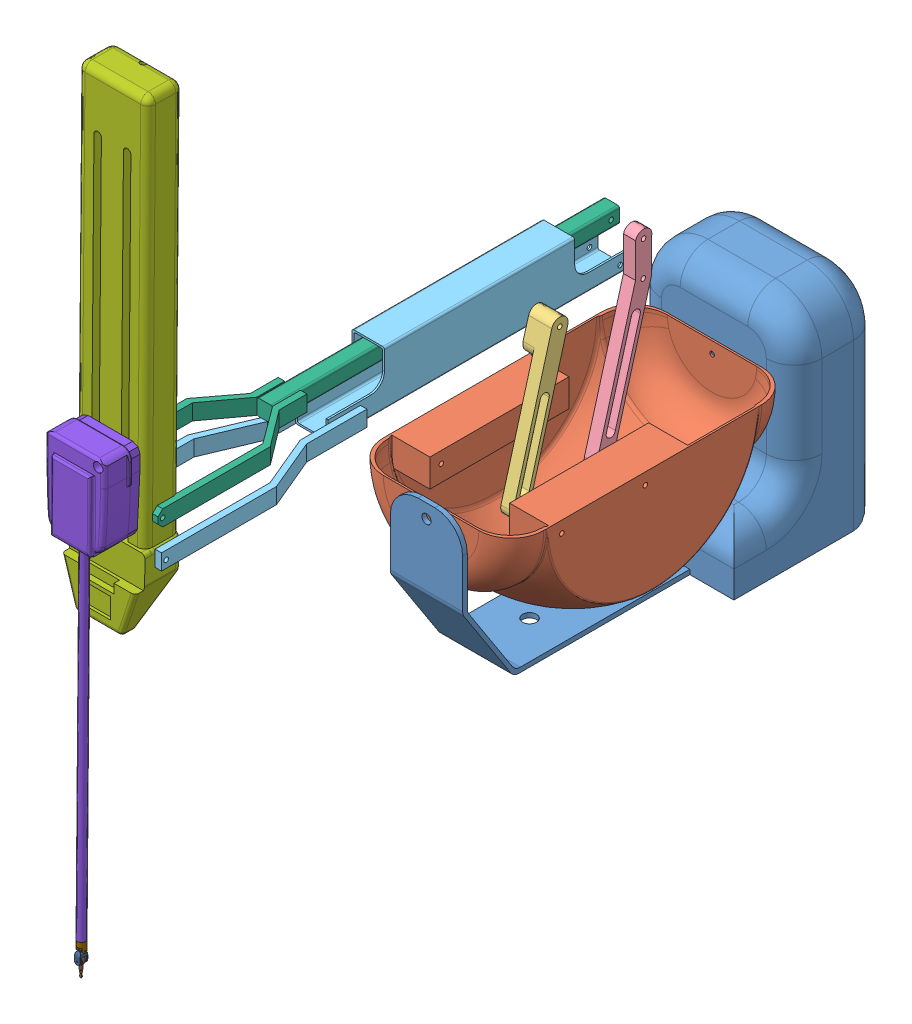
SolidWorks assembly ActiveSection, configuration Default. Lengths in mm.
Overall size (173.42 821.79 791.73).
11 component instances, 11 part files, 26 mates.
Components (placement in the parent):
- L1-1: L1 [Default] at (-68.7537 -23.5534 169.1519) size (173 228 404)
- L2-1: L2 [Default] at (-29.7537 67.7343 50.5284) size (173.42 143 305)
- LP12-1: LP12 [Default] at (-0.2537 151.1135 121.8589) x (0 -0.267998 -0.963419) z (1 0 0) size (18 173.91 25)
- LP11-1: LP11 [Default] at (-0.2537 95.7196 44.9923) x (0 -0.269759 -0.962928) z (1 0 0) size (27.97 209.62 13)
- LP21-1: LP21 [Default] at (-27.3141 259.523 7.7454) size (96 58 534)
- LP22-1: LP22 [Default] at (0.8884 224.0342 7.4385) size (90 17 534)
- L3-2: L3 [Default] at (-26.1906 634.2205 507.9112) x (1 0 0) z (0 -0.999966 0.008294) size (82 50 500)
- L4-1: L4 [Default] at (-29.7537 215.3788 576.9644) x (1 0 0) z (0 -0.999966 0.008294) size (68.49 43.05 464)
- L5-1: L5 [Default] at (-29.7537 -151.4086 580.0064) x (1 0 0) z (0 -0.999966 0.008294) size (8.32 8.32 11)
- L6-1: L6 [Default] at (-66.6018 -121.6279 583.9596) x (0 -0.999966 0.008294) z (0 -0.008294 -0.999966) size (14.9 6.29 8.98)
- L7-1: L7 [Default] at (-30.0037 -174.0474 580.2442) x (1 0 0) z (0 -0.999966 0.008294) size (6 3.3 19.83)
Mates (geometry in assembly coordinates):
- Coincident1: coincident anti-aligned: plane of L1-1 through (9.2463 70.2343 203.0301) normal (0 0 -1); plane of L2-1 through (-29.7537 67.7343 203.0301) normal (0 0 1)
- Concentric1: concentric aligned: cylinder of L1-1 through (-29.7537 55.2343 -195.9699) axis (0 0 1) radius 5; circle of L2-1
- Coincident2: coincident anti-aligned: plane of L2-1 through (12.7463 37.7343 160.8722) normal (-1 0 0); plane of LP12-1 through (12.7463 205.4449 106.7454) normal (1 0 0)
- Concentric2: concentric anti-aligned: cylinder of L2-1 through (-116.4646 55.2343 148.5301) axis (1 0 0) radius 2.5; cylinder of LP12-1 through (12.7463 55.2343 148.5301) axis (-1 0 0) radius 2.5
- Coincident3: coincident anti-aligned: plane of LP12-1 through (-12.2537 205.4449 106.7454) normal (-1 0 0); plane of LP21-1 through (-12.2537 253.4449 331.7454) normal (1 0 0)
- Concentric3: concentric anti-aligned: cylinder of LP12-1 through (12.7463 205.4449 106.7454) axis (-1 0 0) radius 2.5; cylinder of LP21-1 through (-47.2537 205.4449 106.7454) axis (1 0 0) radius 2.5
- Coincident4: coincident anti-aligned: plane of L2-1 through (12.7463 37.7343 160.8722) normal (-1 0 0); plane of LP11-1 through (12.7463 242.4436 16.4385) normal (1 0 0)
- Concentric4: concentric anti-aligned: cylinder of L2-1 through (-116.4646 55.2343 58.5301) axis (1 0 0) radius 2.5; cylinder of LP11-1 through (12.7463 55.2343 58.5301) axis (-1 0 0) radius 2.5
- Concentric5: concentric anti-aligned: cylinder of LP11-1 through (12.7463 205.4449 16.7454) axis (-1 0 0) radius 2.5; cylinder of LP21-1 through (-47.2537 205.4449 16.7454) axis (1 0 0) radius 2.5
- Concentric6: concentric anti-aligned: cylinder of LP11-1 through (12.7463 242.4436 16.4385) axis (-1 0 0) radius 2.5; cylinder of LP22-1 through (-75.7537 242.4436 16.4385) axis (1 0 0) radius 2.5
- Distance1: distance = 8 mm anti-aligned: plane of LP22-1 through (-22.2537 248.9436 381.4385) normal (1 0 0); plane of LP21-1 through (-14.2537 251.4449 331.7454) normal (-1 0 0)
- Concentric10: concentric aligned: cylinder of LP22-1 through (-75.7537 242.4436 536.4385) axis (1 0 0) radius 2.5; cylinder of L3-2 through (-70.7537 242.4436 536.4385) axis (1 0 0) radius 2.5
- Concentric11: concentric aligned: cylinder of LP21-1 through (-77.7537 205.4449 536.7454) axis (1 0 0) radius 2.5; cylinder of L3-2 through (-70.7537 205.4449 536.7454) axis (1 0 0) radius 2.5
- Coincident8: coincident anti-aligned: plane of LP21-1 through (-70.7537 214.4449 541.7454) normal (1 0 0); plane of L3-2 through (-70.7537 134.24 512.3351) normal (-1 0 0)
- Coincident9: coincident anti-aligned: plane of L3-2 through (-67.7537 214.5524 549.6703) normal (0 0.008294 0.999966); plane of L4-1 through (-61.8537 222.606 549.6035) normal (0 -0.008294 -0.999966)
- Coincident10: coincident anti-aligned: plane of L3-2 through (-41.6537 574.2912 516.6856) normal (-1 0 0); plane of L4-1 through (-41.6537 282.4583 562.1575) normal (1 0 0)
- Coincident11: coincident anti-aligned: plane of L4-1 through (-29.7537 -151.4086 580.0064) normal (0 -0.999966 0.008294); plane of L5-1 through (-29.7537 -151.4086 580.0064) normal (0 0.999966 -0.008294)
- Concentric12: concentric aligned: cylinder of L4-1 through (-29.7537 -151.4086 580.0064) axis (0 0.999966 -0.008294) radius 4.2; cylinder of L5-1 through (-29.7537 -162.4082 580.0977) axis (0 0.999966 -0.008294) radius 4.16
- Concentric13: concentric anti-aligned: cylinder of L5-1 through (-33.9137 -160.5083 580.0819) axis (1 0 0) radius 0.7; cylinder of L6-1 through (-26.9037 -160.5083 580.0819) axis (-1 0 0) radius 0.65
- Distance2: distance = 2 mm anti-aligned: plane of L6-1 through (-28.5537 -158.7208 578.567) normal (1 0 0); plane of L5-1 through (-26.5537 -163.3001 575.9449) normal (-1 0 0)
- Distance3: distance = 1 mm: plane of L7-1 through (-28.6537 -166.0614 578.5279) normal (0 -0.008294 -0.999966); plane of L6-1 through (-26.9037 -186.329 577.696) normal (0 0.008294 0.999966)
- Concentric14: concentric: cylinder of L6-1 through (-30.0037 -170.2715 584.5623) axis (0 -0.008294 -0.999966) radius 0.65; cylinder of L7-1 through (-30.0037 -170.3212 578.5632) axis (0 0.008294 0.999966) radius 0.65
- Parallel1: parallel aligned: plane of L1-1 through (6.7463 78.2343 -195.9699) normal (0 0 -1); plane of LP11-1 through (12.7463 206.1387 7.7721) normal (0 0 -1)
- Distance4: distance = 5 mm anti-aligned: plane of L3-2 through (11.2463 214.6519 561.6699) normal (0 0.999966 -0.008294); plane of L4-1 through (4.3463 219.6356 559.6785) normal (0 -0.999966 0.008294)
- Parallel2: parallel aligned: plane of L4-1 through (4.3473 296.0685 587.4455) normal (0 0.008294 0.999966); plane of L6-1 through (-30.1037 -170.5731 584.3655) normal (0 0.008294 0.999966)
- Parallel3: parallel aligned: plane of L6-1 through (-30.1037 -170.5731 584.3655) normal (0 0.008294 0.999966); plane of L7-1 through (-31.0837 -187.1445 580.6528) normal (0 0.008294 0.999966)
